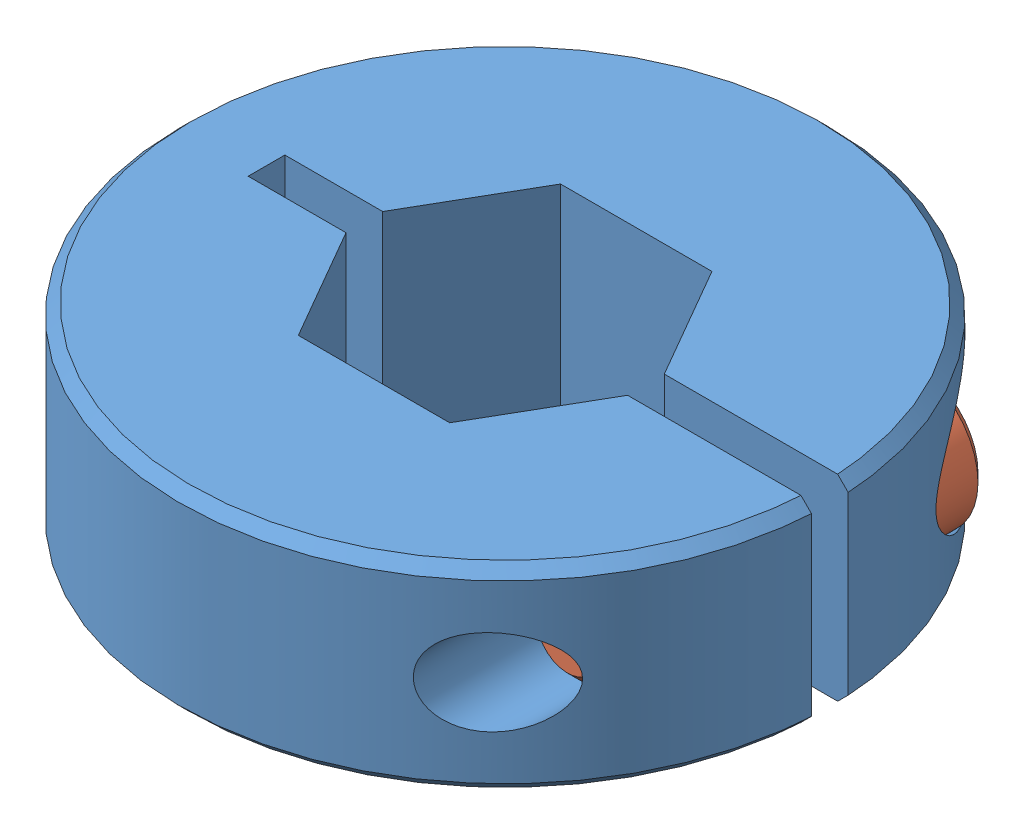
SolidWorks assembly Hex_Collar, configuration Default. Lengths in mm.
Overall size (31.47 9.53 31.5).
2 component instances, 2 part files, 0 mates.
Components (placement in the parent):
- am-1238 Clamp Only-1: am-1238 Clamp Only [Default] at origin size (31.47 9.53 31.5)
- am-1238 Screw Only_91251A194-1: am-1238 Screw Only_91251A194 [Default] at (10.7699 4.7625 7.747) size (6.86 6.86 17.11)
